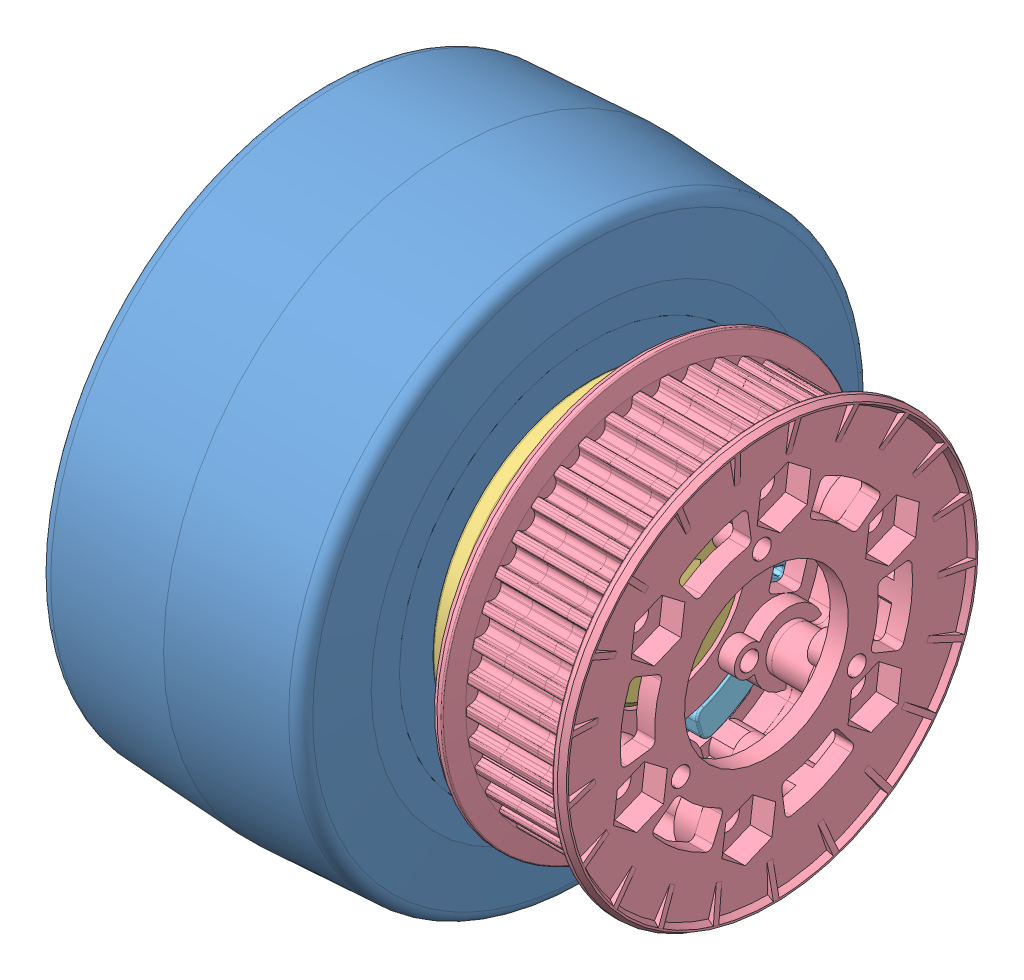
SolidWorks assembly wheel live axis, configuration Default. Lengths in mm.
Overall size (93.59 101.6 101.6).
6 component instances, 6 part files, 14 mates.
Components (placement in the parent):
- colson wheel-1: colson wheel [Default] at (7.8533 43.785 105.4789) size (47.77 101.6 101.6)
- hub live axis-1: hub live axis [Default] at (-17.6186 43.785 105.4789) x (0 -0.5 -0.866025) z (1 0 0) size (34.92 34.92 48.22)
- versahub .5 in hex-2: versahub .5 in hex [Default] at (44.4376 43.785 105.4789) x (-1 0 0) z (0 0 -1) size (12.7 55.88 55.88)
- pulley-1: pulley [Default] at (42.8501 43.785 105.4789) x (0 0.128986 0.991646) z (-1 0 0) size (73 73 23.01)
- versahub 1.125 in bearing pilot-1: versahub 1.125 in bearing pilot [Default] at (38.0876 43.785 105.4789) x (0 -0.011158 0.999938) z (0 0.999938 0.011158) size (55.88 12.7 55.88)
- hex bearing for live axis-1: hex bearing for live axis [Default] at (-30.3186 43.785 105.4789) x (0 -0.5 0.866025) z (0 0.866025 0.5) size (31.12 7.94 31.12)
Mates (geometry in assembly coordinates):
- Coincident1: coincident anti-aligned: plane of colson wheel-1 through (-16.0311 91.2495 29.2789) normal (-1 0 0); plane of hub live axis-1 through (-16.0311 43.785 105.4789) normal (1 0 0)
- Concentric1: concentric aligned: cylinder of colson wheel-1 through (-64.7182 43.785 105.4789) axis (-1 0 0) radius 15.1257; cylinder of hub live axis-1 through (25.2439 43.785 105.4789) axis (-1 0 0) radius 15.24
- Coincident2: coincident anti-aligned: plane of pulley-1 through (41.2626 43.785 105.4789) normal (-1 0 0); plane of versahub 1.125 in bearing pilot-1 through (41.2626 43.785 105.4789) normal (1 0 0)
- Concentric3: concentric aligned: cylinder of pulley-1 through (44.4376 43.785 105.4789) axis (-1 0 0) radius 25.5; cylinder of versahub 1.125 in bearing pilot-1 through (44.4376 43.785 105.4789) axis (-1 0 0) radius 25.5
- Coincident7: coincident anti-aligned: plane of versahub .5 in hex-2 through (34.9126 43.785 105.4789) normal (1 0 0); plane of versahub 1.125 in bearing pilot-1 through (34.9126 43.785 105.4789) normal (-1 0 0)
- Coincident8: coincident anti-aligned: plane of versahub .5 in hex-2 through (34.9126 43.785 105.4789) normal (1 0 0); plane of versahub 1.125 in bearing pilot-1 through (34.9126 43.785 105.4789) normal (-1 0 0)
- Concentric5: concentric anti-aligned: cylinder of versahub .5 in hex-2 through (44.4376 43.785 105.4789) axis (-1 0 0) radius 14.2949; cylinder of versahub 1.125 in bearing pilot-1 through (34.9126 43.785 105.4789) axis (1 0 0) radius 14.3
- Concentric6: concentric aligned: cylinder of colson wheel-1 through (-64.7182 43.785 105.4789) axis (-1 0 0) radius 15.1257; cylinder of pulley-1 through (62.2626 43.785 105.4789) axis (-1 0 0) radius 14.3
- Parallel1: parallel aligned: plane of hub live axis-1 through (-22.3811 36.4234 105.4789) normal (0 0.866025 -0.5); plane of versahub .5 in hex-2 through (44.4376 36.438 105.4789) normal (0 0.866025 -0.5)
- Parallel2: parallel aligned: plane of hub live axis-1 through (-22.3811 47.4659 99.1035) normal (0 0 1); plane of versahub .5 in hex-2 through (44.4376 47.4586 99.1162) normal (0 0 1)
- Coincident9: coincident anti-aligned: plane of colson wheel-1 through (31.7376 102.7058 29.2789) normal (1 0 0); plane of versahub .5 in hex-2 through (31.7376 71.725 105.4789) normal (-1 0 0)
- Coincident12: coincident anti-aligned: plane of hub live axis-1 through (-22.3811 43.785 105.4789) normal (-1 0 0); plane of hex bearing for live axis-1 through (-22.3811 40.61 110.9781) normal (1 0 0)
- Concentric8: concentric aligned: circle of hub live axis-1; circle of hex bearing for live axis-1
- Parallel4: parallel aligned: plane of hub live axis-1 through (-22.3811 40.1042 99.1035) normal (0 0.866025 0.5); plane of hex bearing for live axis-1 through (-30.3186 36.4412 105.4789) normal (0 0.866025 0.5)
